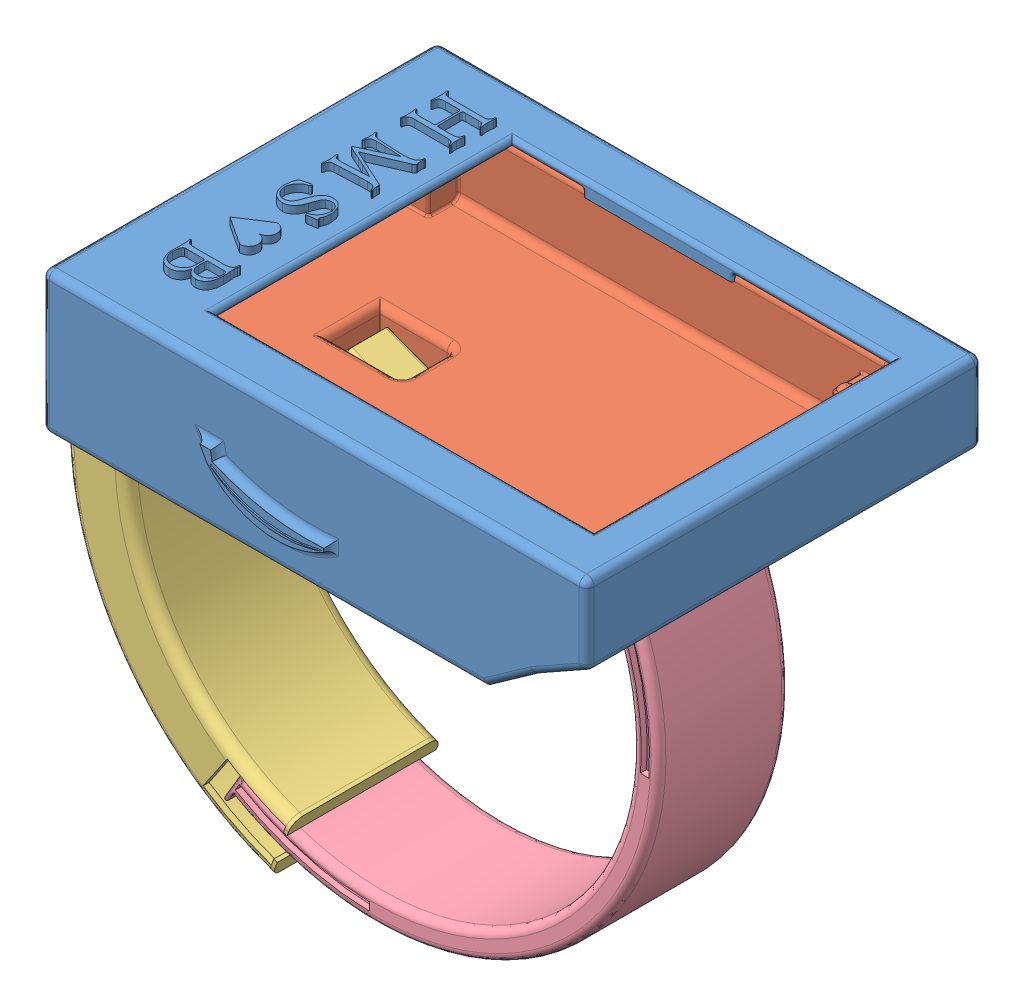
SolidWorks assembly Assem1, configuration Default. Lengths in mm.
Overall size (85.52 72.11 55.2).
4 component instances, 4 part files, 10 mates.
Components (placement in the parent):
- Cover-1: Cover [Default] at (15.2964 27.2212 66.3418) size (73 20 55.2)
- Connector-1: Connector [Default] at (9.2964 27.2212 92.5418) x (0 0 -1) z (1 0 0) size (50 18 70)
- LeftBand-1: LeftBand [Default] at (-11.2037 31.2212 92.5418) x (-1 0 0) z (0 0 -1) size (38.97 59.82 23.74)
- Intermediate Band-1: Intermediate Band [Default] at (-10.6613 -4.2691 92.9918) x (0.029522 -0.999564 0) z (0 0 -1) size (55.44 59.13 17.68)
Mates (geometry in assembly coordinates):
- Concentric1: concentric: circle of Cover-1; circle of Connector-1
- Coincident1: coincident: plane of Cover-1 through (50.2964 45.2212 117.3418) normal (0 -1 0); plane of Connector-1 through (9.2964 45.2212 92.5418) normal (0 1 0)
- Parallel1: parallel: plane of Cover-1 through (15.2964 27.2212 117.3418) normal (0 0 -1); plane of Connector-1 through (-20.7036 35.2212 117.5418) normal (0 0 1)
- Coincident3: coincident: plane of Cover-1 through (9.2964 38.2212 116.5418) normal (0 0 -1); plane of Connector-1 through (9.2964 38.2212 116.5418) normal (0 0 1)
- Coincident4: coincident: plane of Connector-1 through (-3.7036 28.2212 84.0418) normal (0 1 0); plane of LeftBand-1 through (-11.2036 28.2212 102.5418) normal (0 -1 0)
- Coincident5: coincident: plane of Connector-1 through (-3.7036 30.2212 101.0418) normal (0 0 -1); plane of LeftBand-1 through (-4.2036 29.9212 101.0418) normal (0 0 1)
- Coincident6: coincident: plane of Connector-1 through (4.2964 27.2212 92.5418) normal (-1 0 0); plane of LeftBand-1 through (4.2964 31.2212 92.5418) normal (1 0 0)
- Concentric2: concentric: cylinder of LeftBand-1 through (6.2963 13.7394 92.5418) axis (0 0 -1) radius 33.3182; cylinder of Intermediate Band-1 through (6.2963 13.7394 92.9918) axis (0 0 -1) radius 34.5172
- Parallel3: parallel: plane of LeftBand-1 through (-4.4366 -16.9565 82.5418) normal (0 0 -1); plane of Intermediate Band-1 through (36.88 29.7417 84.2418) normal (0 0 -1)
- Coincident9: coincident: plane of LeftBand-1 through (-4.4366 -16.9565 101.7418) normal (0 0 -1); plane of Intermediate Band-1 through (36.88 29.7417 101.7418) normal (0 0 1)
